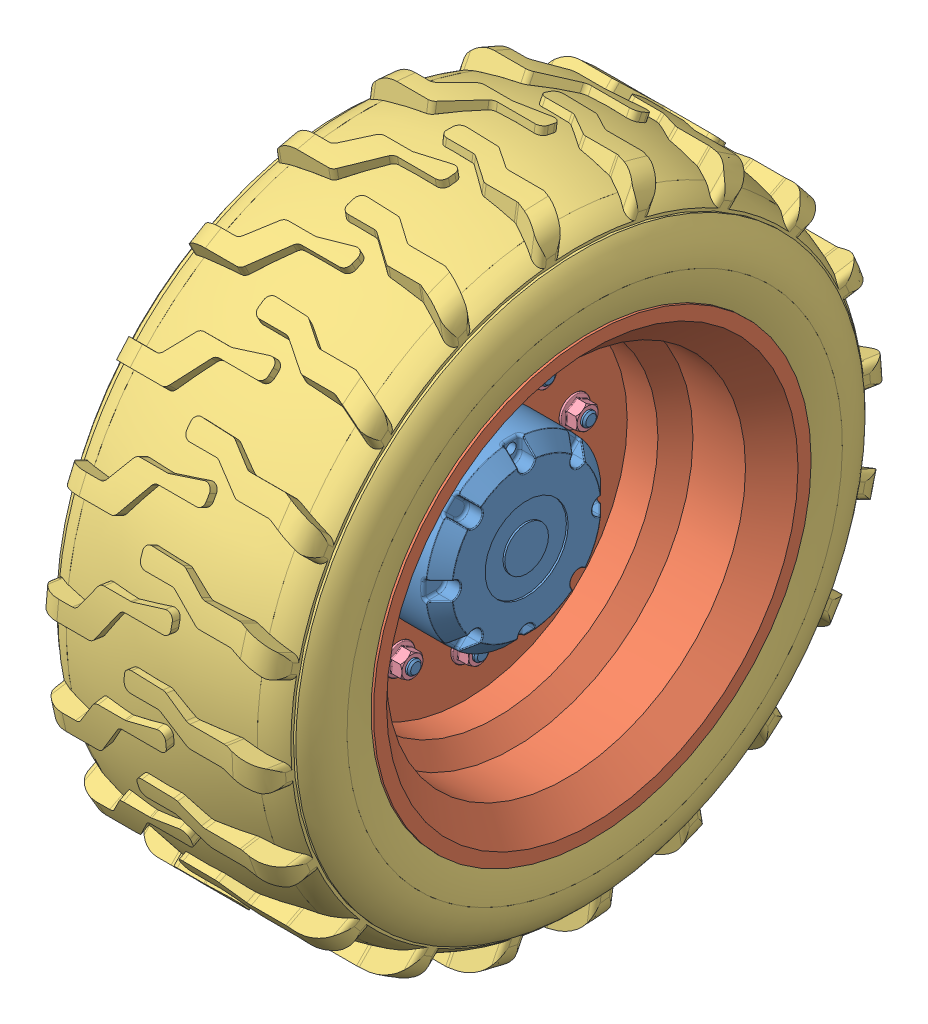
SolidWorks assembly Tire Sub Assembly, configuration Default. Lengths in mm.
Overall size (367.75 833.89 833.89).
13 component instances, 4 part files, 25 mates.
Components (placement in the parent):
- 15. Axle-1: 15. Axle [Default] at (370.5079 7.8342 176.4257) size (290 300 300)
- 16. Rim-1: 16. Rim [Default] at (475.5079 7.8342 176.4257) size (300 500 500)
- 17. Tire-1: 17. Tire [Default] at (475.5079 7.8342 176.4257) x (1 0 0) z (0 0.148505 0.988912) size (305.49 733.15 733.15)
- hex flange nut_am-1: hex flange nut_am [B18.2.2.4M - Hex flange nut, M16 x 2 --N] at (496.5079 113.0064 100.0136) x (0 0 -1) z (1 0 0) size (34.5 34.5 16)
- hex flange nut_am-2: hex flange nut_am [B18.2.2.4M - Hex flange nut, M16 x 2 --N] at (496.5079 137.8342 176.4257) x (0 0 -1) z (1 0 0) size (34.5 34.5 16)
- hex flange nut_am-3: hex flange nut_am [B18.2.2.4M - Hex flange nut, M16 x 2 --N] at (496.5079 113.0064 252.8378) x (0 0 -1) z (1 0 0) size (34.5 34.5 16)
- hex flange nut_am-4: hex flange nut_am [B18.2.2.4M - Hex flange nut, M16 x 2 --N] at (496.5079 48.0064 300.063) x (0 0 -1) z (1 0 0) size (34.5 34.5 16)
- hex flange nut_am-5: hex flange nut_am [B18.2.2.4M - Hex flange nut, M16 x 2 --N] at (496.5079 -32.338 300.063) x (0 0 -1) z (1 0 0) size (34.5 34.5 16)
- hex flange nut_am-6: hex flange nut_am [B18.2.2.4M - Hex flange nut, M16 x 2 --N] at (496.5079 -97.338 252.8378) x (0 0 -1) z (1 0 0) size (34.5 34.5 16)
- hex flange nut_am-7: hex flange nut_am [B18.2.2.4M - Hex flange nut, M16 x 2 --N] at (496.5079 -122.1658 176.4257) x (0 0 -1) z (1 0 0) size (34.5 34.5 16)
- hex flange nut_am-8: hex flange nut_am [B18.2.2.4M - Hex flange nut, M16 x 2 --N] at (496.5079 -97.338 100.0136) x (0 0 -1) z (1 0 0) size (34.5 34.5 16)
- hex flange nut_am-9: hex flange nut_am [B18.2.2.4M - Hex flange nut, M16 x 2 --N] at (496.5079 -32.338 52.7883) x (0 0 -1) z (1 0 0) size (34.5 34.5 16)
- hex flange nut_am-10: hex flange nut_am [B18.2.2.4M - Hex flange nut, M16 x 2 --N] at (496.5079 48.0064 52.7883) x (0 0 -1) z (1 0 0) size (34.5 34.5 16)
Mates (geometry in assembly coordinates):
- Concentric1: concentric aligned: cylinder of 20. Rim-1 through (475.5079 7.8342 176.4257) axis (1 0 0) radius 250; cylinder of 21. Tire-1 through (475.5079 7.8342 176.4257) axis (1 0 0) radius 240
- Coincident1: coincident aligned: plane of 20. Rim-1 through (475.5079 7.8342 176.4257) normal (1 0 0); plane of 21. Tire-1 through (475.5079 7.8342 176.4257) normal (1 0 0)
- Concentric2: concentric aligned: cylinder of 19. Axle-1 through (550.5079 7.8342 176.4257) axis (1 0 0) radius 150; cylinder of 20. Rim-1 through (475.5079 7.8342 176.4257) axis (1 0 0) radius 100
- Coincident2: coincident anti-aligned: plane of 19. Axle-1 through (470.5079 157.8342 176.4257) normal (1 0 0); plane of 20. Rim-1 through (470.5079 192.8342 176.4257) normal (-1 0 0)
- Concentric3: concentric anti-aligned: cylinder of 19. Axle-1 through (500.5079 113.0064 100.0136) axis (-1 0 0) radius 8; cylinder of 20. Rim-1 through (470.5079 113.0064 100.0136) axis (1 0 0) radius 8
- Concentric4: concentric aligned: cylinder of 20. Rim-1 through (470.5079 113.0064 100.0136) axis (1 0 0) radius 8; cylinder of hex flange nut_am-1 through (471.4704 113.0064 100.0136) axis (1 0 0) radius 8
- Coincident3: coincident anti-aligned: plane of 20. Rim-1 through (480.5079 192.8342 176.4257) normal (1 0 0); plane of hex flange nut_am-1 through (480.5079 126.8628 100.0136) normal (-1 0 0)
- Concentric5: concentric aligned: cylinder of 20. Rim-1 through (470.5079 137.8342 176.4257) axis (1 0 0) radius 8; cylinder of hex flange nut_am-2 through (471.4704 137.8342 176.4257) axis (1 0 0) radius 8
- Coincident4: coincident anti-aligned: plane of 20. Rim-1 through (480.5079 192.8342 176.4257) normal (1 0 0); plane of hex flange nut_am-2 through (480.5079 151.6906 176.4257) normal (-1 0 0)
- Concentric6: concentric aligned: cylinder of 20. Rim-1 through (470.5079 113.0064 252.8378) axis (1 0 0) radius 8; cylinder of hex flange nut_am-3 through (471.4704 113.0064 252.8378) axis (1 0 0) radius 8
- Coincident5: coincident anti-aligned: plane of 20. Rim-1 through (480.5079 192.8342 176.4257) normal (1 0 0); plane of hex flange nut_am-3 through (480.5079 126.8628 252.8378) normal (-1 0 0)
- Concentric7: concentric aligned: cylinder of 20. Rim-1 through (470.5079 48.0064 300.063) axis (1 0 0) radius 8; cylinder of hex flange nut_am-4 through (471.4704 48.0064 300.063) axis (1 0 0) radius 8
- Coincident6: coincident anti-aligned: plane of 20. Rim-1 through (480.5079 192.8342 176.4257) normal (1 0 0); plane of hex flange nut_am-4 through (480.5079 61.8628 300.063) normal (-1 0 0)
- Concentric8: concentric aligned: cylinder of 20. Rim-1 through (470.5079 -32.338 300.063) axis (1 0 0) radius 8; cylinder of hex flange nut_am-5 through (471.4704 -32.338 300.063) axis (1 0 0) radius 8
- Coincident7: coincident anti-aligned: plane of 20. Rim-1 through (480.5079 192.8342 176.4257) normal (1 0 0); plane of hex flange nut_am-5 through (480.5079 -18.4816 300.063) normal (-1 0 0)
- Concentric9: concentric aligned: cylinder of 20. Rim-1 through (470.5079 -97.338 252.8378) axis (1 0 0) radius 8; cylinder of hex flange nut_am-6 through (471.4704 -97.338 252.8378) axis (1 0 0) radius 8
- Coincident8: coincident anti-aligned: plane of 20. Rim-1 through (480.5079 192.8342 176.4257) normal (1 0 0); plane of hex flange nut_am-6 through (480.5079 -83.4816 252.8378) normal (-1 0 0)
- Concentric10: concentric aligned: cylinder of 20. Rim-1 through (470.5079 -122.1658 176.4257) axis (1 0 0) radius 8; cylinder of hex flange nut_am-7 through (471.4704 -122.1658 176.4257) axis (1 0 0) radius 8
- Coincident9: coincident anti-aligned: plane of 20. Rim-1 through (480.5079 192.8342 176.4257) normal (1 0 0); plane of hex flange nut_am-7 through (480.5079 -108.3094 176.4257) normal (-1 0 0)
- Concentric11: concentric aligned: cylinder of 20. Rim-1 through (470.5079 -97.338 100.0136) axis (1 0 0) radius 8; cylinder of hex flange nut_am-8 through (471.4704 -97.338 100.0136) axis (1 0 0) radius 8
- Coincident10: coincident anti-aligned: plane of 20. Rim-1 through (480.5079 192.8342 176.4257) normal (1 0 0); plane of hex flange nut_am-8 through (480.5079 -83.4816 100.0136) normal (-1 0 0)
- Concentric12: concentric aligned: cylinder of 20. Rim-1 through (470.5079 -32.338 52.7883) axis (1 0 0) radius 8; cylinder of hex flange nut_am-9 through (471.4704 -32.338 52.7883) axis (1 0 0) radius 8
- Coincident11: coincident anti-aligned: plane of 20. Rim-1 through (480.5079 192.8342 176.4257) normal (1 0 0); plane of hex flange nut_am-9 through (480.5079 -18.4816 52.7883) normal (-1 0 0)
- Concentric13: concentric aligned: cylinder of 20. Rim-1 through (470.5079 48.0064 52.7883) axis (1 0 0) radius 8; cylinder of hex flange nut_am-10 through (471.4704 48.0064 52.7883) axis (1 0 0) radius 8
- Coincident12: coincident anti-aligned: plane of 20. Rim-1 through (480.5079 192.8342 176.4257) normal (1 0 0); plane of hex flange nut_am-10 through (480.5079 61.8628 52.7883) normal (-1 0 0)
